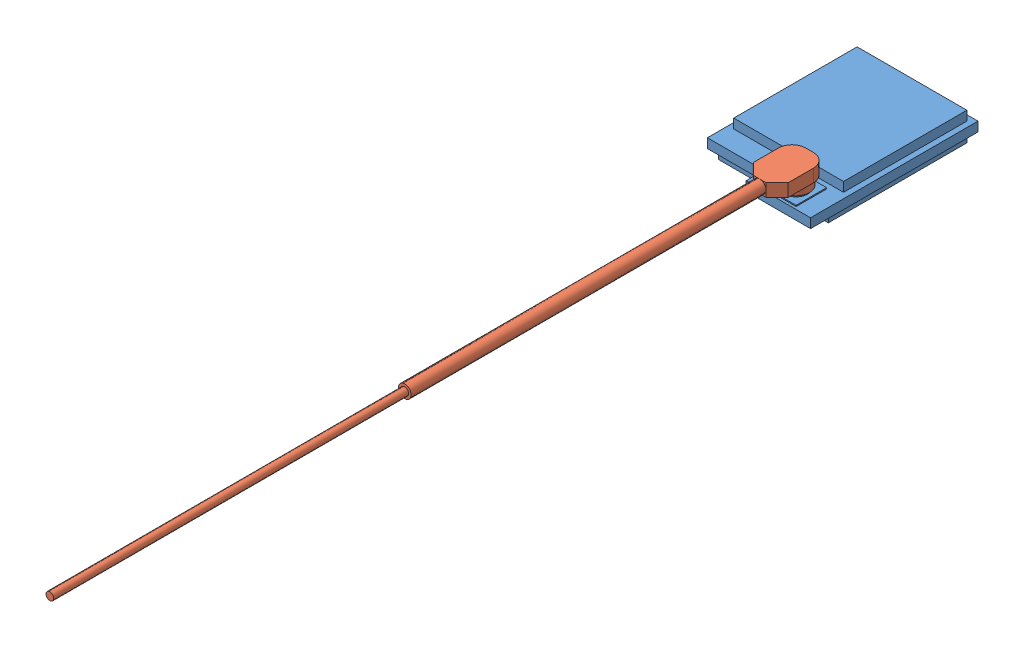
SolidWorks assembly Receiver, configuration Default. Lengths in mm.
Overall size (10.9 4.12 80.79).
2 component instances, 2 part files, 4 mates.
Components (placement in the parent):
- ReceiverChip-1: ReceiverChip [Default] at origin size (10.9 2.97 15.1)
- ReceiverAntenna-1: ReceiverAntenna [Default] at (2.55 1.695 7.785) x (0 0 -1) z (1 0 0) size (68.5 2.1 3.15)
Mates (geometry in assembly coordinates):
- Concentric1: concentric anti-aligned: cylinder of ReceiverChip-1 through (-12.5209 -5.4887 18.6405) axis (0 -1 0) radius 1.025; cylinder of ReceiverAntenna-1 through (-12.5209 -6.4387 18.6405) axis (0 1 0) radius 1.215
- Coincident1: coincident anti-aligned: plane of ReceiverChip-1 through (-12.5209 -5.4887 18.6405) normal (0 1 0); plane of ReceiverAntenna-1 through (-12.5209 -5.4887 19.6755) normal (0 -1 0)
- Parallel1: parallel aligned: plane of ReceiverChip-1 through (-9.6209 -6.7587 18.6405) normal (1 0 0); plane of ReceiverAntenna-1 through (-10.9459 -4.3387 21.9255) normal (1 0 0)
- Coincident3: coordinate: point of ReceiverChip-1
